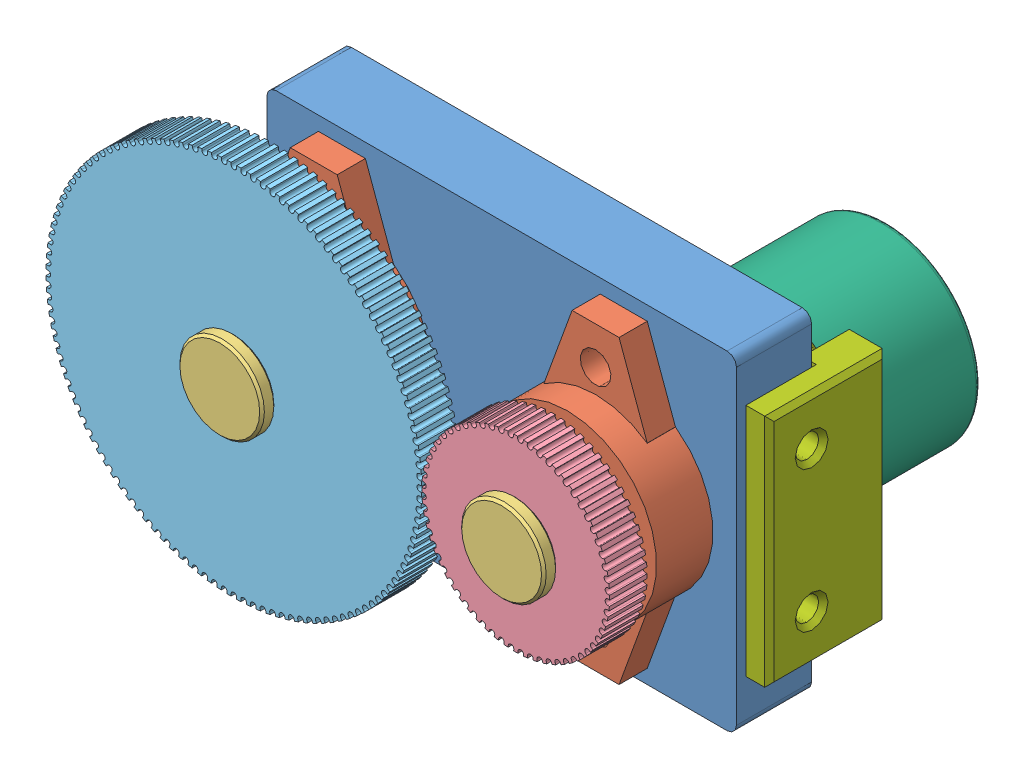
SolidWorks assembly gear_box_back, configuration Default. Lengths in mm.
Overall size (163.01 105.62 82).
11 component instances, 7 part files, 13 mates.
Components (placement in the parent):
- holder-1: holder [Default] at (12.8649 69.8201 86.4972) size (113 87 16)
- wg_assembly-1: wg_assembly [Default] at (-22.7926 54.053 92.4972) x (0 0 1) z (0 1 0) size (33 38 64)
  - bearing_h-1: bearing_h [Default] at origin size (15 38 64)
  - roll_fixator-1: roll_fixator [Default] at (23 0 0) x (0 0 -1) z (1 0 0) size (18 18 33)
- wg_assembly-2: wg_assembly [Default] at (37.2074 54.053 92.4972) x (0 0 1) z (0 1 0) size (33 38 64)
  - bearing_h-1: bearing_h [Default] at origin size (15 38 64)
  - roll_fixator-1: roll_fixator [Default] at (23 0 0) x (0 0 -1) z (1 0 0) size (18 18 33)
- spindel_wheel_encoder-1: spindel_wheel_encoder [Default] at (37.2074 54.053 115.4972) x (0 0 -1) z (1 0 0) size (8 40 40)
- spindel_wheel_encoder-80-1: spindel_wheel_encoder-80 [Default] at (-22.7926 54.053 107.4972) x (0 0 1) z (-0.913442 0.40697 0) size (8 79.99 79.99)
- encoder-1: encoder [Default] at (37.2074 54.053 36.4972) size (40 40 59)
- sensor_holder-1: sensor_holder [Default] at (39.0544 52.9619 99.9054) x (0 0 -1) z (-0.508605 -0.861 0) size (25.43 62.18 60.77)
Mates (geometry in assembly coordinates):
- Coincident1: coincident anti-aligned: plane of holder-1 through (12.8649 69.8201 92.4972) normal (0 0 1); plane of wg_assembly-1/bearing_h-1 through (-22.7926 54.053 92.4972) normal (0 0 -1)
- Concentric2: concentric anti-aligned: cylinder of holder-1 through (-22.7926 78.053 82.4972) axis (0 0 1) radius 3.5; cylinder of wg_assembly-1/bearing_h-1 through (-22.7926 78.053 98.4972) axis (0 0 -1) radius 3.2759
- Coincident3: coincident anti-aligned: plane of wg_assembly-2/bearing_h-1 through (37.2074 54.053 107.4972) normal (0 0 1); plane of spindel_wheel_encoder-1 through (37.2074 54.053 107.4972) normal (0 0 -1)
- Concentric3: concentric aligned: cylinder of wg_assembly-2/roll_fixator-1 through (37.2074 54.053 85.4972) axis (0 0 1) radius 6; cylinder of spindel_wheel_encoder-1 through (37.2074 54.053 107.4972) axis (0 0 1) radius 6
- Concentric4: concentric anti-aligned: cylinder of wg_assembly-1/roll_fixator-1 through (-22.7926 54.053 85.4972) axis (0 0 1) radius 6; cylinder of spindel_wheel_encoder-80-1 through (-22.7926 54.053 115.4972) axis (0 0 -1) radius 6
- Coincident4: coincident anti-aligned: plane of wg_assembly-1/bearing_h-1 through (-22.7926 54.053 107.4972) normal (0 0 1); plane of spindel_wheel_encoder-80-1 through (-22.7926 54.053 107.4972) normal (0 0 -1)
- Parallel5: parallel: plane of holder-1 through (-41.7926 86.053 92.4972) normal (0 1 0); plane of wg_assembly-2/bearing_h-1 through (26.2074 86.053 98.4972) normal (0 1 0)
- Coincident5: coincident anti-aligned: plane of encoder-1 through (37.2074 54.053 75.4972) normal (0 0 1); plane of sensor_holder-1 through (37.2074 54.053 75.4972) normal (0 0 -1)
- Concentric5: concentric anti-aligned: cylinder of encoder-1 through (37.2074 54.053 75.4972) axis (0 0 -1) radius 20; cylinder of sensor_holder-1 through (37.2074 54.053 171.5192) axis (0 0 1) radius 25
- Concentric6: concentric aligned: cylinder of wg_assembly-2/roll_fixator-1 through (37.2074 54.053 95.4972) axis (0 0 -1) radius 3; cylinder of encoder-1 through (37.2074 54.053 95.4972) axis (0 0 -1) radius 3
- Concentric7: concentric anti-aligned: cylinder of holder-1 through (37.2074 54.053 82.4972) axis (0 0 1) radius 9; cylinder of wg_assembly-2/bearing_h-1 through (37.2074 54.053 104.4972) axis (0 0 -1) radius 19
- Coincident6: coincident anti-aligned: plane of wg_assembly-2/roll_fixator-1 through (37.2074 54.053 95.4972) normal (0 0 -1); circle of encoder-1
- Parallel6: parallel anti-aligned: plane of holder-1 through (61.2074 69.8201 86.4972) normal (1 0 0); plane of sensor_holder-1 through (61.2074 52.9619 99.9054) normal (-1 0 0)
